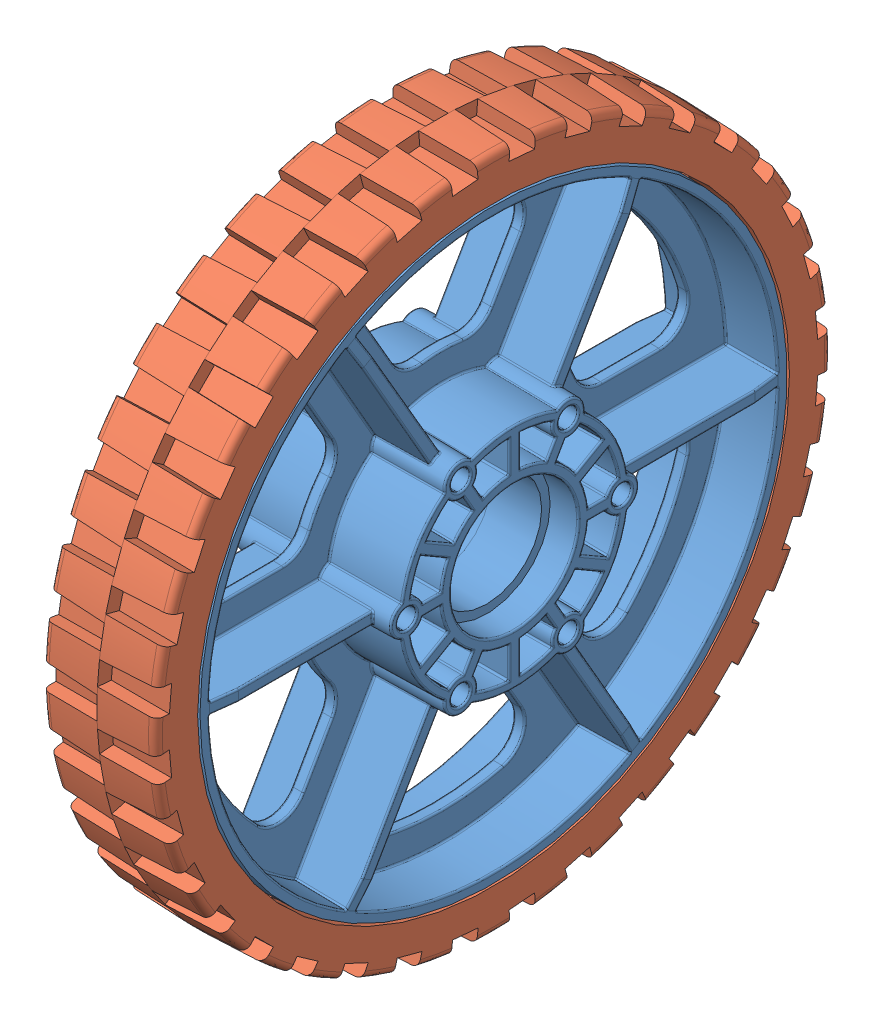
SolidWorks assembly am-940a-6-HiGrip-, configuration Default. Lengths in mm.
Overall size (34.93 152.4 152.4).
2 component instances, 2 part files, 0 mates.
Components (placement in the parent):
- 6 wheel Rev 4-1: 6 wheel Rev 4 [Default] at (-52.6446 9.4231 21.378) size (34.93 132.08 132.08)
- 6 wheel tread II-1: 6 wheel tread II [Default] at (-65.3446 9.4231 21.378) x (0 0 -1) z (1 0 0) size (152.4 152.4 25.58)
